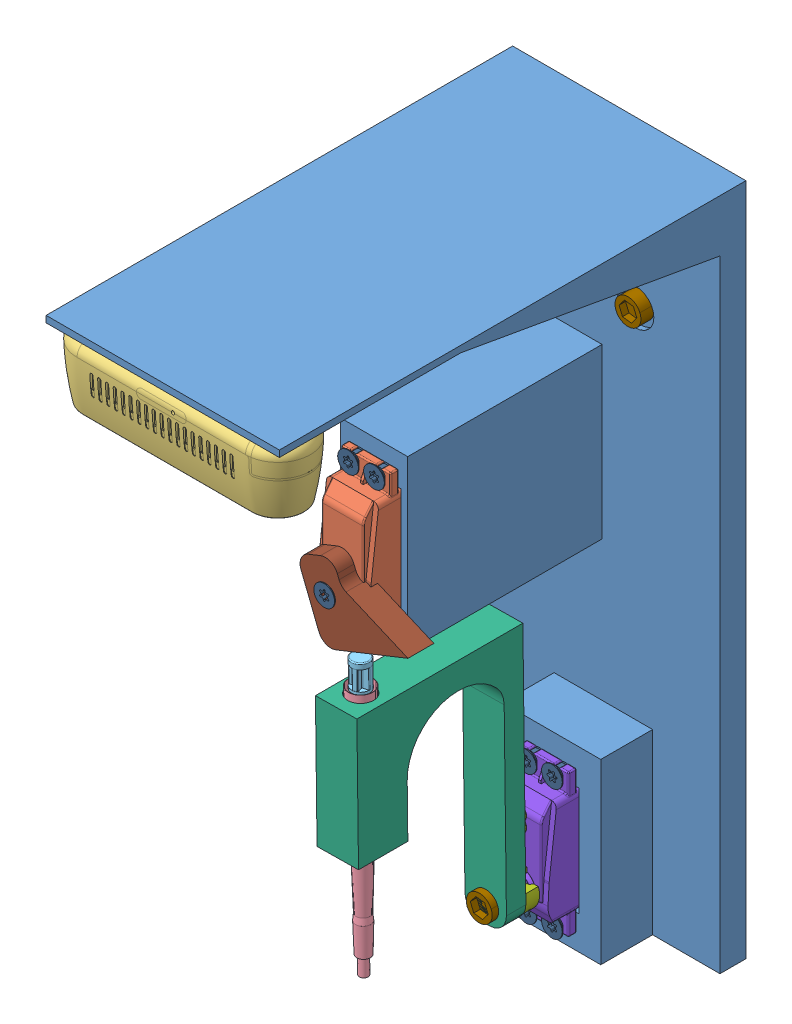
SolidWorks assembly End-effector-assembly, configuration Default. Lengths in mm.
Overall size (90.59 260 203.18).
25 component instances, 12 part files, 44 mates.
Components (placement in the parent):
- end-effector-frame-1: end-effector-frame [Default] at (85.6666 80.0909 119.2018) size (90 260 180)
- servo_motor-1: servo_motor [Default] at (72.1666 74.2909 175.8518) x (0 -1 0) z (-1 0 0) size (55.1 45.65 20.12)
- Part1^End-effector-assembly-1: Part1^End-effector-assembly [Default] at origin (virtual)
- Intel Realsense D435-1: Intel Realsense D435 [Default] at (86.1714 173.0715 287.7605) x (-1 0 0) z (0 0 1) size (90.13 25.28 25.4)
- biopsy-assembly-2: biopsy-assembly [Default] at (85.823 -56.2928 221.7849) x (-0.048096 -0.000596 0.998843) z (-0.998766 -0.012383 -0.0481) size (10.58 105.67 10.58)
  - biopsy-body-1: biopsy-body [Default] at origin size (9.5 96.04 9.5)
  - biopsy-piston-2: biopsy-piston [Default] at (0 7.4683 0) x (-0.951126 0 0.308804) z (-0.308804 0 -0.951126) size (8.4 95.11 8.4)
- biopsy-shield-1: biopsy-shield [Default] at (85.2854 -12.934 221.7849) x (0.999923 0.012398 0) z (0 0 1) size (16 100 65.18)
- servo_horn_2-1: servo_horn_2 [Default] at (85.8234 -56.3307 163.6018) x (0.999923 0.012398 0) z (0 0 1) size (14.8 34.72 5.92)
- servo_motor_2-1: servo_motor_2 [Default] at (85.8234 -46.3807 120.8518) x (0 -1 0) z (-1 0 0) size (55.1 45.65 20.12)
- bolt_2-2: bolt_2 [Default] at (73.1666 126.5909 132.2018) x (-0.923728 -0.383049 0) z (0 0 -1) size (10 10 35)
- bolt_2-3: bolt_2 [Default] at (98.1666 151.5909 132.2018) x (-0.923728 -0.383049 0) z (0 0 -1) size (10 10 35)
- bolt_2-4: bolt_2 [Default] at (73.1666 151.5909 132.2018) x (0.923728 0.383049 0) z (0 0 -1) size (10 10 35)
- bolt_2-5: bolt_2 [Default] at (98.1666 126.5909 132.2018) x (-0.923728 -0.383049 0) z (0 0 -1) size (10 10 35)
- screw_1-1: screw_1 [Default] at (67.1666 99.3409 206.9018) size (8 8 5)
- screw_1-2: screw_1 [Default] at (77.1666 99.3409 206.9018) size (8 8 5)
- screw_1-3: screw_1 [Default] at (67.1666 49.2409 206.9018) size (8 8 5)
- screw_1-4: screw_1 [Default] at (77.1666 49.2409 206.9018) size (8 8 5)
- screw_1-5: screw_1 [Default] at (90.8234 -71.4307 151.9018) size (8 8 5)
- screw_1-6: screw_1 [Default] at (80.8234 -21.3307 151.9018) size (8 8 5)
- screw_1-7: screw_1 [Default] at (80.8234 -71.4307 151.9018) size (8 8 5)
- screw_1-8: screw_1 [Default] at (90.8234 -21.3307 151.9018) x (0.131652 -0.991296 0) z (0 0 1) size (8 8 5)
- screw_1-9: screw_1 [Default] at (72.1666 64.3409 221.1018) size (8 8 5)
- bolt_2-6: bolt_2 [Default] at (85.8234 -56.3307 177.2518) x (-0.923728 -0.383049 0) z (0 0 -1) size (10 10 35)
- servo-punching-horn-custom2-1: servo-punching-horn-custom2 [Default] at (71.3705 45.9416 212.8018) x (0.929084 0.369868 0) z (0 0 1) size (35 28.7 10)
Mates (geometry in assembly coordinates):
- Perpendicular1: perpendicular: plane of end-effector-frame-1 through (85.6666 80.0909 149.2018) normal (0 0 1); plane of Intel Realsense D435-1 through (118.6714 177.5715 287.7605) normal (0 1 0)
- Parallel3: parallel: plane of end-effector-frame-1 through (85.6666 80.0909 149.2018) normal (0 0 1); line of biopsy-assembly-2/biopsy-piston-2 through (84.6313 39.8181 221.7849) axis (0.012398 -0.999923 0)
- Concentric15: concentric anti-aligned: cylinder of biopsy-shield-1 through (85.8234 -56.3307 177.2518) axis (0 0 -1) radius 1.5; cylinder of servo_horn_2-1 through (85.8234 -56.3307 166.1018) axis (0 0 1) radius 3.95
- Parallel7: parallel aligned: plane of biopsy-shield-1 through (92.6884 35.2615 221.7849) normal (0.999923 0.012398 0); plane of servo_horn_2-1 through (89.1732 -56.2891 167.2518) normal (0.999923 0.012398 0)
- Coincident17: coincident anti-aligned: plane of end-effector-frame-1 through (85.6666 80.0909 149.2018) normal (0 0 1); plane of servo_motor_2-1 through (80.8234 -71.4307 149.2018) normal (0 0 -1)
- Coincident26: coincident anti-aligned: plane of end-effector-frame-1 through (85.6666 80.0909 204.2018) normal (0 0 1); plane of servo_motor-1 through (67.1666 99.3409 204.2018) normal (0 0 -1)
- Coincident27: coincident anti-aligned: plane of end-effector-frame-1 through (73.1666 126.5909 127.2018) normal (0 0 1); plane of bolt_2-2 through (73.1666 126.5909 127.2018) normal (0 0 -1)
- Concentric25: concentric aligned: cylinder of end-effector-frame-1 through (73.1666 126.5909 127.2018) axis (0 0 1) radius 7; cylinder of bolt_2-2 through (73.1666 126.5909 127.2018) axis (0 0 1) radius 5
- Coincident28: coincident anti-aligned: plane of end-effector-frame-1 through (98.1666 151.5909 127.2018) normal (0 0 1); plane of bolt_2-3 through (98.1666 151.5909 127.2018) normal (0 0 -1)
- Coincident29: coincident anti-aligned: plane of end-effector-frame-1 through (98.1666 151.5909 127.2018) normal (0 0 1); plane of bolt_2-3 through (98.1666 151.5909 127.2018) normal (0 0 -1)
- Coincident30: coincident anti-aligned: plane of end-effector-frame-1 through (73.1666 151.5909 127.2018) normal (0 0 1); plane of bolt_2-4 through (73.1666 151.5909 127.2018) normal (0 0 -1)
- Concentric27: concentric aligned: cylinder of end-effector-frame-1 through (73.1666 151.5909 127.2018) axis (0 0 1) radius 7; cylinder of bolt_2-4 through (73.1666 151.5909 127.2018) axis (0 0 1) radius 5
- Coincident31: coincident anti-aligned: plane of end-effector-frame-1 through (98.1666 126.5909 127.2018) normal (0 0 1); plane of bolt_2-5 through (98.1666 126.5909 127.2018) normal (0 0 -1)
- Concentric28: concentric anti-aligned: cylinder of end-effector-frame-1 through (98.1666 126.5909 127.2018) axis (0 0 1) radius 7; circle of bolt_2-5
- Coincident32: coincident anti-aligned: plane of end-effector-frame-1 through (85.6666 80.0909 204.2018) normal (0 0 1); plane of screw_1-1 through (67.1666 99.3409 204.2018) normal (0 0 -1)
- Coincident33: coincident anti-aligned: plane of end-effector-frame-1 through (85.6666 80.0909 204.2018) normal (0 0 1); plane of screw_1-2 through (77.1666 99.3409 204.2018) normal (0 0 -1)
- Concentric31: concentric aligned: cylinder of servo_motor-1 through (77.1666 99.3409 204.2018) axis (0 0 1) radius 2.075; cylinder of screw_1-2 through (77.1666 99.3409 204.6018) axis (0 0 1) radius 2
- Coincident34: coincident anti-aligned: plane of end-effector-frame-1 through (85.6666 80.0909 204.2018) normal (0 0 1); plane of screw_1-3 through (67.1666 49.2409 204.2018) normal (0 0 -1)
- Concentric32: concentric aligned: cylinder of servo_motor-1 through (67.1666 49.2409 204.2018) axis (0 0 1) radius 2.075; cylinder of screw_1-3 through (67.1666 49.2409 204.6018) axis (0 0 1) radius 2
- Coincident35: coincident anti-aligned: plane of end-effector-frame-1 through (85.6666 80.0909 204.2018) normal (0 0 1); plane of screw_1-4 through (77.1666 49.2409 204.2018) normal (0 0 -1)
- Concentric33: concentric aligned: cylinder of servo_motor-1 through (77.1666 49.2409 204.2018) axis (0 0 1) radius 2.075; cylinder of screw_1-4 through (77.1666 49.2409 204.6018) axis (0 0 1) radius 2
- Coincident36: coincident anti-aligned: plane of end-effector-frame-1 through (85.6666 80.0909 149.2018) normal (0 0 1); plane of screw_1-6 through (80.8234 -21.3307 149.2018) normal (0 0 -1)
- Coincident37: coincident anti-aligned: plane of end-effector-frame-1 through (85.6666 80.0909 149.2018) normal (0 0 1); plane of screw_1-5 through (90.8234 -71.4307 149.2018) normal (0 0 -1)
- Coincident38: coincident anti-aligned: plane of end-effector-frame-1 through (85.6666 80.0909 149.2018) normal (0 0 1); plane of screw_1-7 through (80.8234 -71.4307 149.2018) normal (0 0 -1)
- Coincident39: coincident anti-aligned: plane of end-effector-frame-1 through (85.6666 80.0909 149.2018) normal (0 0 1); plane of screw_1-8 through (90.8234 -21.3307 149.2018) normal (0 0 -1)
- Concentric34: concentric aligned: cylinder of servo_motor_2-1 through (80.8234 -71.4307 149.2018) axis (0 0 1) radius 2.075; cylinder of screw_1-7 through (80.8234 -71.4307 149.6018) axis (0 0 1) radius 2
- Concentric35: concentric aligned: cylinder of servo_motor_2-1 through (90.8234 -71.4307 149.2018) axis (0 0 1) radius 2.075; cylinder of screw_1-5 through (90.8234 -71.4307 149.6018) axis (0 0 1) radius 2
- Concentric36: concentric aligned: cylinder of servo_motor_2-1 through (80.8234 -21.3307 149.2018) axis (0 0 1) radius 2.075; cylinder of screw_1-6 through (80.8234 -21.3307 149.6018) axis (0 0 1) radius 2
- Concentric37: concentric aligned: cylinder of servo_motor_2-1 through (90.8234 -21.3307 149.2018) axis (0 0 1) radius 2.075; cylinder of screw_1-8 through (90.8234 -21.3307 149.6018) axis (0 0 1) radius 2
- Concentric39: concentric anti-aligned: cylinder of biopsy-shield-1 through (85.8234 -56.3307 177.2518) axis (0 0 -1) radius 1.5; cylinder of bolt_2-6 through (85.8234 -56.3307 172.2518) axis (0 0 1) radius 5
- Coincident44: coincident anti-aligned: plane of end-effector-frame-1 through (30.6666 177.5715 329.2018) normal (0 -1 0); plane of Intel Realsense D435-1 through (118.6714 177.5715 287.7605) normal (0 1 0)
- Coincident46: coincident anti-aligned: plane of biopsy-shield-1 through (85.2854 -12.934 167.2518) normal (0 0 -1); plane of servo_horn_2-1 through (85.8234 -56.3307 167.2518) normal (0 0 1)
- Concentric43: concentric aligned: cylinder of servo_horn_2-1 through (85.8234 -56.3307 167.2518) axis (0 0 -1) radius 7.4; cylinder of servo_motor_2-1 through (85.8234 -56.3307 166.5018) axis (0 0 -1) radius 1
- Concentric44: concentric anti-aligned: cylinder of servo_horn_2-1 through (85.8234 -56.3307 167.2518) axis (0 0 -1) radius 7.4; cylinder of bolt_2-6 through (85.8234 -56.3307 172.2518) axis (0 0 1) radius 5
- Parallel17: parallel anti-aligned: plane of servo_horn_2-1 through (85.8234 -56.3307 161.3518) normal (0 0 -1); plane of servo_motor_2-1 through (85.8234 -56.3307 162.5018) normal (0 0 1)
- Coincident50: coincident anti-aligned: plane of servo_horn_2-1 through (85.8234 -56.3307 161.3518) normal (0 0 -1); plane of servo_motor_2-1 through (85.8234 -46.3807 161.3518) normal (0 0 1)
- Concentric49: concentric aligned: cylinder of biopsy-assembly-2/biopsy-body-1 through (85.823 -56.2928 221.7849) axis (0.012398 -0.999923 0) radius 4.75; cylinder of biopsy-shield-1 through (84.689 35.1623 221.7849) axis (0.012398 -0.999923 0) radius 6.5
- Concentric50: concentric aligned: cylinder of servo_motor-1 through (67.1666 99.3409 204.2018) axis (0 0 1) radius 2.075; circle of screw_1-1
- Concentric51: concentric aligned: cylinder of end-effector-frame-1 through (67.1666 99.3409 194.2018) axis (0 0 1) radius 2.25; circle of screw_1-1
- Concentric52: concentric aligned: cylinder of end-effector-frame-1 through (77.1666 99.3409 194.2018) axis (0 0 1) radius 2.25; circle of screw_1-2
- Concentric53: concentric aligned: cylinder of end-effector-frame-1 through (80.8234 -21.3307 139.2018) axis (0 0 1) radius 2.25; circle of screw_1-6
- Concentric54: concentric aligned: cylinder of end-effector-frame-1 through (90.8234 -21.3307 139.2018) axis (0 0 1) radius 2.25; circle of screw_1-8
- Coincident51: coincident anti-aligned: plane of servo_motor-1 through (72.1666 64.3409 217.5018) normal (0 0 1); plane of servo-punching-horn-custom2-1 through (72.1666 64.3409 217.5018) normal (0 0 -1)
- Concentric56: concentric anti-aligned: circle of servo_motor-1; circle of servo-punching-horn-custom2-1
